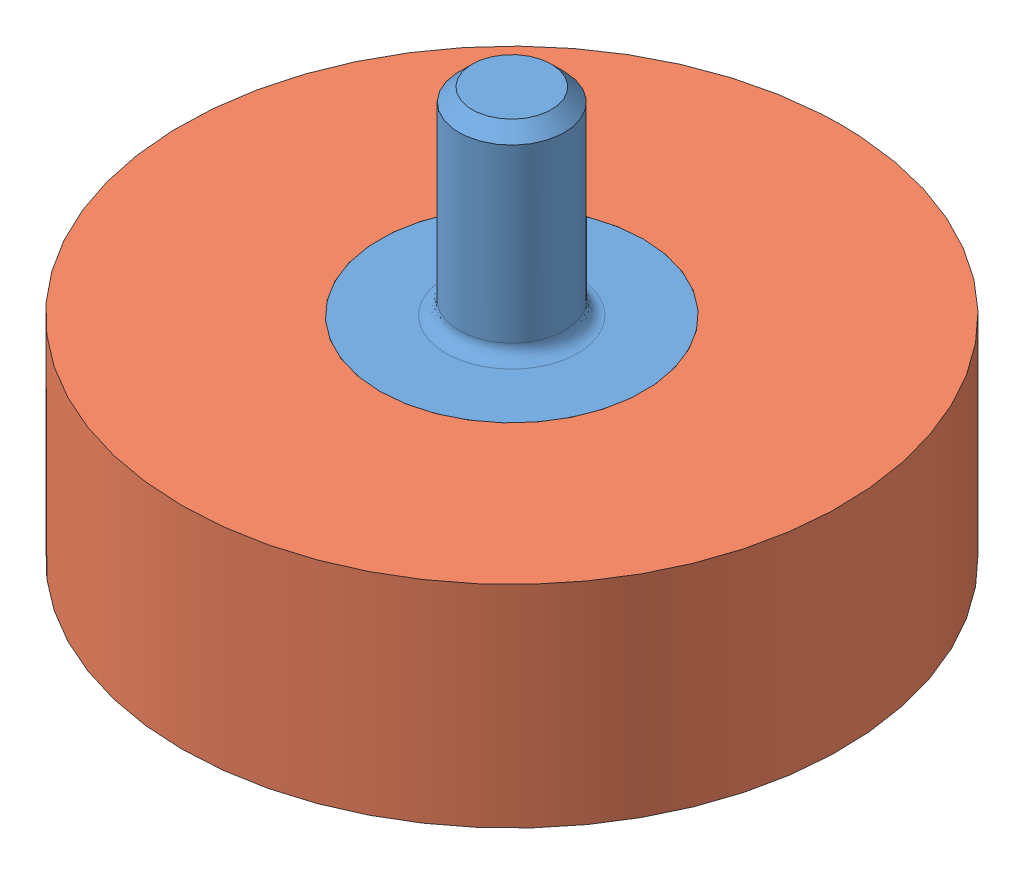
SolidWorks assembly 胶轮1, configuration 默认. Lengths in mm.
Overall size (50 37 50).
2 component instances, 2 part files, 1 mates.
Components (placement in the parent):
- 轮毂1-1: 轮毂1 [默认] at origin size (20 37 20)
- 胶1-2: 胶1 [默认] at (0 22 0) x (0 -1 0) z (0 0 1) size (16 50 50)
Mates (geometry in assembly coordinates):
- 重合2: coincident: circle of assembly; circle of assembly; circle of 轮毂1-1; circle of 胶1-2
